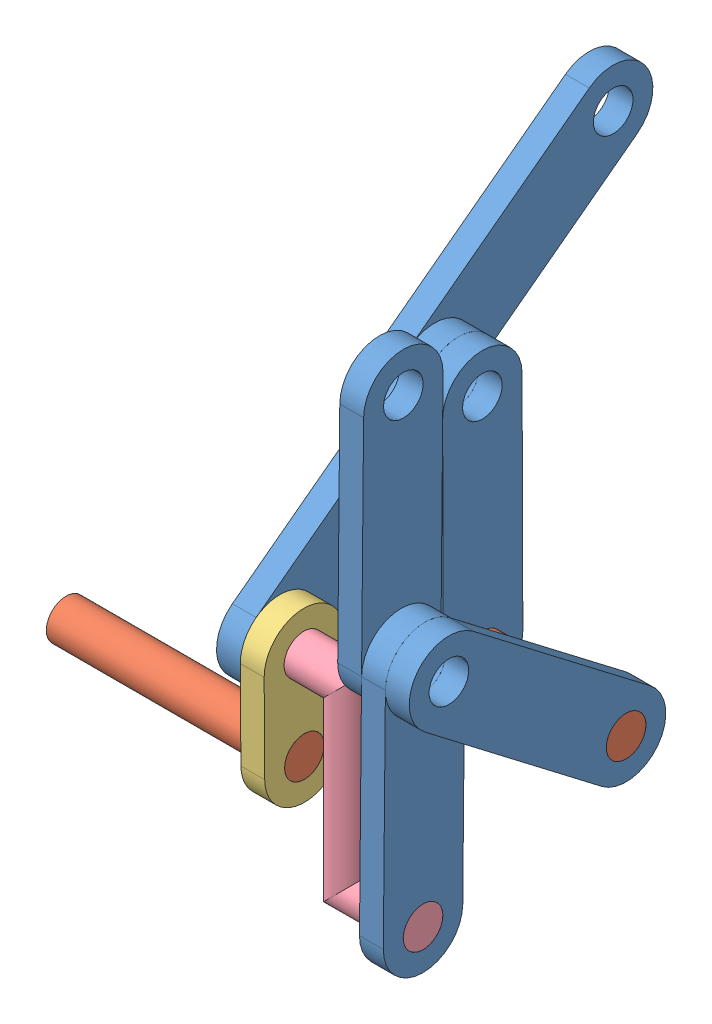
SolidWorks assembly Ensamblaje1, configuration Predeterminado. Lengths in mm.
Overall size (96 136.06 117.87).
10 component instances, 4 part files, 19 mates.
Components (placement in the parent):
- BC-ABM-1: BC-ABM [Predeterminado] at (-21.8164 51.444 124.5601) x (0 0.600574 -0.799569) z (-1 0 0) size (76.2 20 6)
- Eje-1: Eje [Predeterminado] at (-75.8164 11.7582 147.436) x (0 0 -1) z (1 0 0) size (10 10 60)
- BC-ABM-2: BC-ABM [Predeterminado] at (-15.8164 40.493 102.5454) x (0 0.999994 0.003385) z (-1 0 0) size (76.2 20 6)
- BC-ABM-4: BC-ABM [Predeterminado] at (-27.8164 85.1962 79.6243) x (0 0.600574 -0.799569) z (-1 0 0) size (76.2 20 6)
- OAM-2: OAM [Predeterminado] at (-21.8164 22.9822 147.5051) x (0 0.999981 0.00616) z (1 0 0) size (42.4 20 6)
- GANCHO-2: GANCHO [Predeterminado] at (14.1836 -10.3022 147.574) x (1 0 0) z (0 0 -1) size (36 54.46 10)
- BC-ABM-9: BC-ABM [Predeterminado] at (14.1836 18.4794 147.3084) x (0 0.999957 -0.009228) z (-1 0 0) size (76.2 20 6)
- BC-ABM-10: BC-ABM [Predeterminado] at (20.1836 29.2182 125.2936) x (0 0.608275 0.793727) z (-1 0 0) size (76.2 20 6)
- Eje-3: Eje [Predeterminado] at (-39.8164 11.7104 102.4479) x (0 0 -1) z (1 0 0) size (10 10 60)
- BC-ABM-11: BC-ABM [Predeterminado] at (8.1836 74.677 146.7897) x (0 0.999957 -0.009228) z (-1 0 0) size (76.2 20 6)
Mates (geometry in assembly coordinates):
- Coincidente2: coincident: circle of BC-ABM-1; circle of BC-ABM-2
- Coincidente4: coincident: circle of BC-ABM-1; circle of BC-ABM-4
- Paralelo1: parallel: plane of BC-ABM-1; plane of BC-ABM-4 through (-33.8164 56.7888 115.792) normal (0 -0.742705 -0.669619)
- Coincidente7: coincident: cylinder of Eje-1 through (-15.8164 11.7582 147.436) axis (-1 0 0) radius 5; circle of OAM-2
- Coincidente8: coincident: circle of BC-ABM-1; circle of OAM-2
- Coincidente9: coincident: circle of Eje-1; circle of OAM-2
- Coincidente18: coincident: circle of OAM-2; circle of GANCHO-2
- Concéntrica7: concentric: cylinder of OAM-2 through (-15.8164 26.5833 164.2282) axis (-1 0 0) radius 5; cylinder of GANCHO-2 through (1.7836 26.5833 164.2282) axis (-1 0 0) radius 5
- Paralelo5: parallel: plane of Eje-1 through (-75.8164 11.7582 147.436) normal (0 1 0); plane of GANCHO-2 through (14.1836 -17.8767 164.2282) normal (0 -1 0)
- Perpendicular1: perpendicular: plane of Eje-1 through (-75.8164 11.7582 147.436) normal (0 0 -1); plane of GANCHO-2 through (14.1836 -17.8767 164.2282) normal (1 0 0)
- Perpendicular2: perpendicular: plane of Eje-1 through (-75.8164 11.7582 147.436) normal (1 0 0); plane of GANCHO-2 through (14.1836 -17.8767 164.2282) normal (0 0 -1)
- Concéntrica12: concentric: cylinder of GANCHO-2 through (14.1836 -17.8767 164.2282) axis (-1 0 0) radius 5; cylinder of BC-ABM-9 through (8.1836 -17.8767 164.2282) axis (1 0 0) radius 5
- Coincidente31: coincident: circle of GANCHO-2; circle of BC-ABM-9
- Coincidente32: coincident: circle of BC-ABM-9; circle of BC-ABM-10
- Concéntrica13: concentric: cylinder of BC-ABM-2 through (-21.8164 11.7104 102.4479) axis (1 0 0) radius 5; cylinder of Eje-3 through (20.1836 11.7104 102.4479) axis (-1 0 0) radius 5
- Concéntrica14: concentric: cylinder of BC-ABM-10 through (14.1836 11.7104 102.4479) axis (1 0 0) radius 5; cylinder of Eje-3 through (20.1836 11.7104 102.4479) axis (-1 0 0) radius 5
- Coincidente33: coincident: circle of BC-ABM-10; circle of Eje-3
- Coincidente34: coincident: circle of BC-ABM-9; circle of BC-ABM-11
- Paralelo10: parallel: plane of BC-ABM-9; plane of BC-ABM-11
